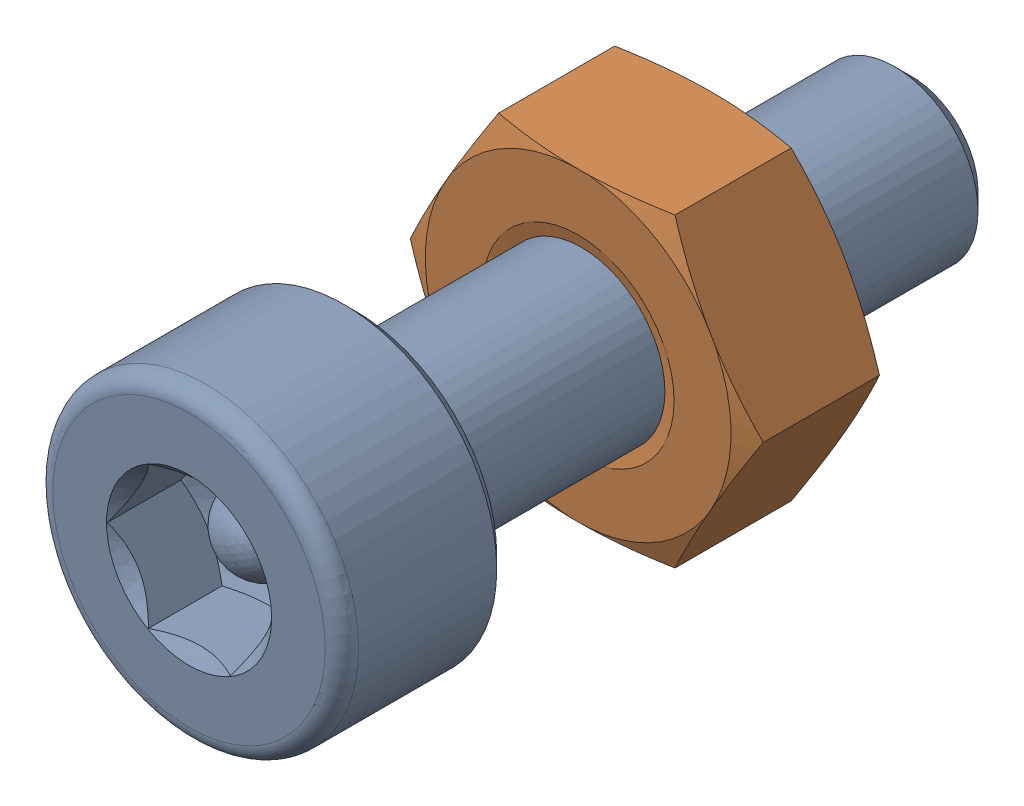
SolidWorks assembly Screw and Nut M3x010_016-1, configuration Varsayılan. Lengths in mm.
Overall size (6.35 5.5 13.14).
2 component instances, 2 part files, 0 mates.
Components (placement in the parent):
- M3x10-Screw015-1-1: M3x10-Screw015-1 [Varsayılan] at origin size (5.5 5.5 13.14)
- M3-Nut047-1-1: M3-Nut047-1 [Varsayılan] at (0 0 -4) x (-1 0 0) z (0 0 -1) size (6.35 5.5 2.4)
